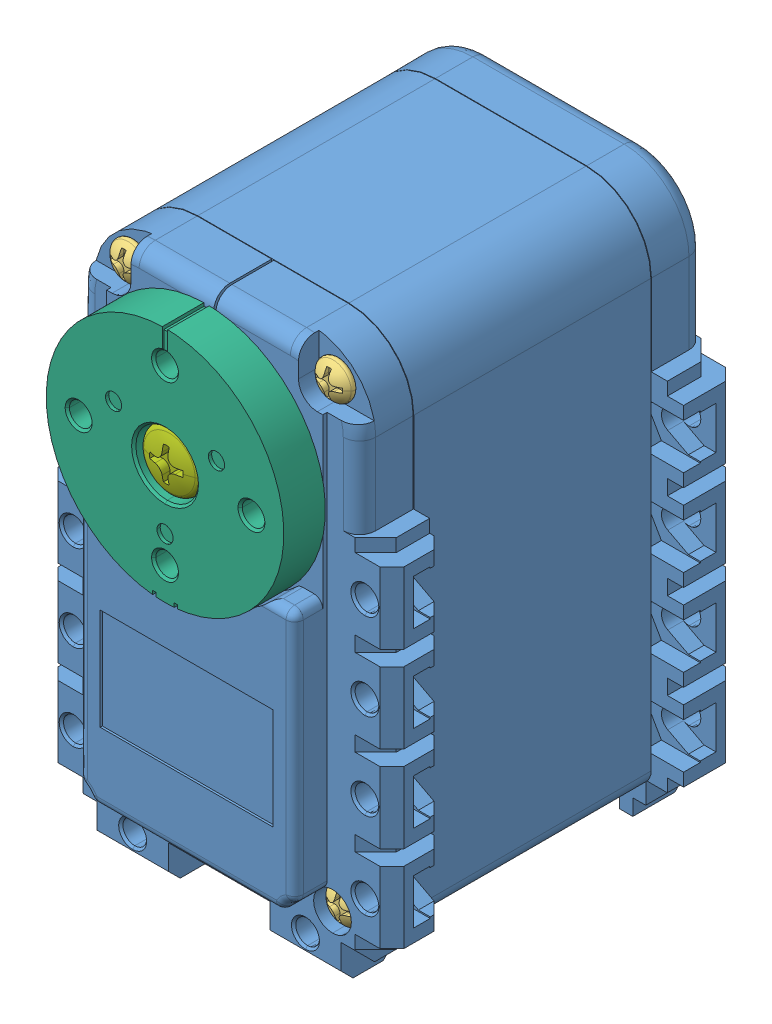
SolidWorks assembly AX-12A.stp, configuration Default. Lengths in mm.
Overall size (32 50.01 40.05).
12 component instances, 7 part files, 0 mates.
Components (placement in the parent):
- ASM0002_ASM.stp-1: ASM0002_ASM.stp [Default] at origin size (32 50.01 40.05)
  - PRT0001.stp-1: PRT0001.stp [Default] at origin size (32 50.01 38)
  - PRT0002.stp-1: PRT0002.stp [Default] at (0 0 -2) x (-1 0 0) z (0 0 1) size (6.5 6.5 5.5)
  - PRT0003.stp-1: PRT0003.stp [Default] at (9.5 8.5 14.5) x (-1 0 0) z (0 1 0) size (3.5 30.65 3.5)
  - PRT0003.stp-2: PRT0003.stp [Default] at (-9.5 8.5 14.5) x (-1 0 0) z (0 1 0) size (3.5 30.65 3.5)
  - PRT0003.stp-3: PRT0003.stp [Default] at (10.5 -33 14.5) x (-1 0 0) z (0 1 0) size (3.5 30.65 3.5)
  - PRT0003.stp-4: PRT0003.stp [Default] at (-10.5 -33 14.5) x (-1 0 0) z (0 1 0) size (3.5 30.65 3.5)
  - PRT0004.stp-1: PRT0004.stp [Default] at (5.05 -15.19 -9.75) x (1 0 0) z (0 1 0) size (9.9 9.4 4.9)
  - PRT0004.stp-2: PRT0004.stp [Default] at (-4.95 -15.19 -9.75) x (1 0 0) z (0 1 0) size (9.9 9.4 4.9)
  - PRT0005.stp-1: PRT0005.stp [Default] at (0 0 -18.4) x (-1 0 0) z (0 1 0) size (4.98 7 4.98)
  - PRT0006.stp-1: PRT0006.stp [Default] at (0 0 19.16) x (0 1 0) z (0 0 1) size (22 22 6.7)
  - PRT0007.stp-1: PRT0007.stp [Default] at (0 0 19.48) x (-1 0 0) z (0 1 0) size (5.5 9.57 5.5)
